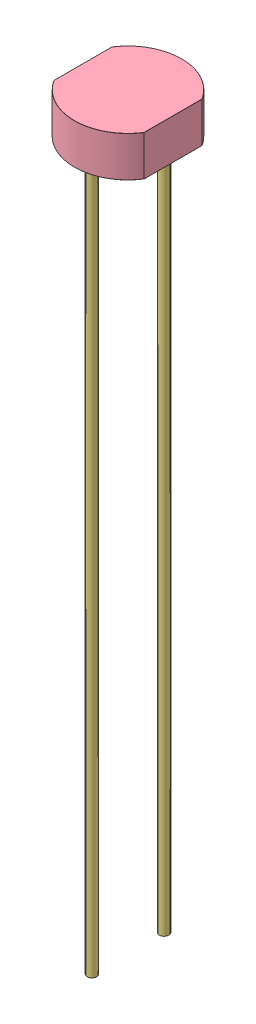
SolidWorks assembly LDR cell thru-hole leaded, configuration Default. Lengths in mm.
Overall size (4.25 35.23 5.05).
4 component instances, 4 part files, 16 mates.
Components (placement in the parent):
- Ceramic base^LDR cell thru-hole leaded-1: Ceramic base^LDR cell thru-hole leaded [Default] x (1 0 0) z (0 1 0) size (4.2 5 1.7) (virtual)
- Electrodes^LDR cell thru-hole leaded-1: Electrodes^LDR cell thru-hole leaded [Default] x (1 0 0) z (0 1 0) size (4 4.8 0.05) (virtual)
- Leads^LDR cell thru-hole leaded-1: Leads^LDR cell thru-hole leaded [Default] x (1 0 0) z (0 1 0) size (0.65 4.05 35.2) (virtual)
- Part16^LDR cell thru-hole leaded-1: Part16^LDR cell thru-hole leaded [Default] x (1 0 0) z (0 1 0) size (4.25 5.05 1.9) (virtual)
Mates (geometry in assembly coordinates):
- InPlace1: in place: plane of ? through (0 0 0) normal (0 1 0); moOrthogonalPlaneRef_w of ? through (0 0 0) normal (0 0 -1); line of ? through (55 -55 0) axis (0 0 1); unknown of ?
- Coincident1: coincident: plane of Ceramic base^LDR cell thru-hole leaded-1; plane of assembly
- Coincident2: coincident: plane of ? through (0 0 0) normal (0 0 -1)
- Coincident3: coincident: line of ? through (2.75 -2.75 0) axis (0 0 1)
- InPlace2: in place: plane of ? through (0 0 0) normal (0 1 0); plane of ? through (0 0 0) normal (0 1 0); plane of ? through (0 0 0) normal (0 1 0); plane of ? through (0 0 0) normal (0 0 -1); plane of ? through (0 0 0) normal (0 1 0); line of ? through (55 -55 0) axis (0 0 1); plane of ? through (0 0 0) normal (0 1 0); unknown of ?
- Coincident4: coincident: plane of Ceramic base^LDR cell thru-hole leaded-1; plane of Electrodes^LDR cell thru-hole leaded-1
- Coincident5: coincident: moOrthogonalPlaneRef_w of Ceramic base^LDR cell thru-hole leaded-1 through (0 0 0) normal (0 0 -1); plane of Electrodes^LDR cell thru-hole leaded-1 through (0 0 0) normal (0 0 -1)
- Coincident6: coincident: moOrthogonalPlaneRef_w of Ceramic base^LDR cell thru-hole leaded-1 through (0 0 0) normal (-1 0 0); plane of Electrodes^LDR cell thru-hole leaded-1
- InPlace3: in place: plane of ? through (0 0 0) normal (0 1 0); plane of ? through (0 0 0) normal (0 0 -1); line of ? through (55 -55 0) axis (0 0 1); unknown of ?
- Coincident7: coincident: plane of Leads^LDR cell thru-hole leaded-1; plane of assembly
- Coincident8: coincident: plane of ? through (0 0 0) normal (0 0 -1)
- Coincident9: coincident: line of ? through (2.2275 -2.2275 0) axis (0 0 1)
- InPlace4: in place: plane of ? through (0 0 0) normal (0 1 0); plane of ? through (0 0 0) normal (0 0 -1); line of ? through (55 -55 0) axis (0 0 1); unknown of ?
- Coincident10: coincident: plane of Part16^LDR cell thru-hole leaded-1; plane of assembly
- Coincident11: coincident: plane of ? through (0 0 0) normal (0 0 -1)
- Coincident12: coincident: line of ? through (2.7775 -2.7775 0) axis (0 0 1)
